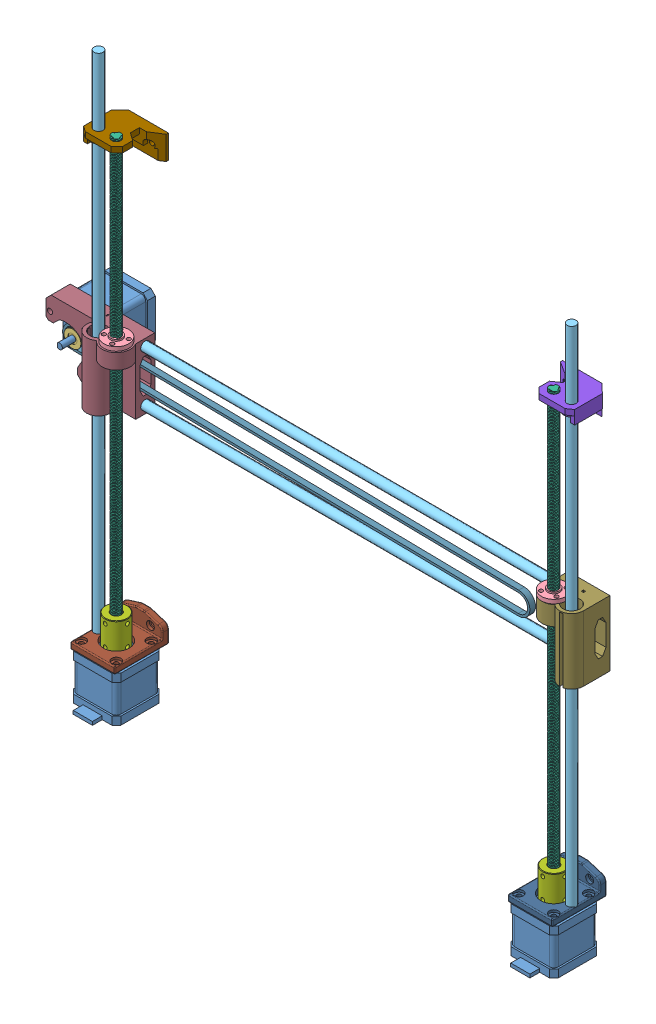
SolidWorks assembly XAssembly, configuration Default. Lengths in mm.
Overall size (485.02 523.02 93.11).
22 component instances, 14 part files, 37 mates.
Components (placement in the parent):
- 40-42 motor-1: 40-42 motor [Standard] at (83.3654 18.4973 -13.9547) x (-1 0 0) z (0 0 -1) size (42 64 50.7)
- 40-42 motor-2: 40-42 motor [Standard] at (-304.6346 18.4973 -13.9547) x (-1 0 0) z (0 0 -1) size (42 64 50.7)
- 624U pillow-1: 624U pillow [Standard] at (-70.3846 223.0937 -25.0811) x (1 0 0) z (0 -1 0) size (13 4 13)
- 2GT-pulley-1: 2GT-pulley [Standard] at (-298.4371 388.8614 -49.1082) x (0 0 1) z (0 1 0) size (16 15 15)
- flanged lead screw nut-1: flanged lead screw nut [Default] at (-380.1347 299.5237 42.4453) x (-0.892252 0 0.451538) z (0 -1 0) size (22 22 19.88)
- flanged lead screw nut-2: flanged lead screw nut [Default] at (7.8652 299.5237 42.4453) x (0.837169 0 0.546944) z (0 -1 0) size (22 22 19.88)
- 40-42 motor-3: 40-42 motor [Standard] at (-354.4079 323.9237 -22.4949) x (-1 0 0) z (0 1 0) size (42 64 50.7)
- BedSlider-1: BedSlider [Default] at (-396.8878 512.0237 35.3611) x (0.113678 0 -0.993518) z (0 -1 0) size (8 8 450)
- BedSlider-2: BedSlider [Default] at (19.3272 512.0237 36.7178) x (-0.378404 0 -0.925641) z (0 -1 0) size (8 8 450)
- Z threaded rod-1: Z threaded rod [Standard] at (-380.1346 84.0237 42.4453) x (0 0 -1) z (0 1 0) size (8.01 8.01 375.98)
- Z threaded rod-2: Z threaded rod [Standard] at (7.8394 454.0237 42.4545) x (-1 0 0) z (0 -1 0) size (8.01 8.01 375.98)
- Z coupler-1: Z coupler [Standard] at (-380.1346 75.0237 42.4453) size (20 26 20)
- Z coupler-2: Z coupler [Standard] at (7.8654 75.0237 42.4453) size (20 26 20)
- ztop holder Right-1: ztop holder Right [Default] at (-30.6346 447.0237 42.4453) x (-1 0 0) z (0 0 -1) size (43 21 35.75)
- ztop holder Left-1: ztop holder Left [Default] at (-380.1346 447.0237 42.4453) x (-1 0 0) z (0 0 -1) size (43 21 35.75)
- Y motor holder right-1: Y motor holder right [Default] at (7.8654 60.0237 42.4453) size (39.5 20 48)
- Y motor holder left-1: Y motor holder left [Default] at (-380.1346 60.0237 42.4453) size (39.5 20 48)
- Right z holder-1: Right z holder [Default] at (15.6154 267.0237 18.9453) x (0 1 0) z (1 0 0) size (58 34.5 38.04)
- Motor Mount-2: Motor Mount [Default] at (-369.4576 296.0237 35.9453) x (-1 0 0) z (0 0 -1) size (81.27 58 36)
- BedSlider-3: BedSlider [Default] at (33.1119 291.8257 20.521) x (0 0 -1) z (-1 0 0) size (8 8 450)
- BedSlider-4: BedSlider [Default] at (-420.7175 244.9609 20.2907) x (0 0.24335 -0.969938) z (1 0 0) size (8 8 450)
- belt-1: belt [Default] at (-397.4115 269.2854 25.1733) size (414.43 26.57 5)
Mates (geometry in assembly coordinates):
- Coincident1: coincident aligned: plane of 40-42 motor-1 through (28.8654 20.0237 72.1453) normal (0 -1 0); plane of 40-42 motor-2 through (-359.1346 20.0237 72.1453) normal (0 -1 0)
- Coincident3: coincident aligned: plane of 40-42 motor-1 through (-9.1416 60.0237 21.4453) normal (0 0 -1); plane of 40-42 motor-2 through (-397.1416 60.0237 21.4453) normal (0 0 -1)
- Concentric3: concentric aligned: cylinder of 2GT-pulley-1 through (-429.9079 267.5237 16.0835) axis (0 0 -1) radius 2.5; cylinder of 40-42 motor-3 through (-429.9079 267.5237 43.0315) axis (0 0 -1) radius 2.5
- Coincident12: coincident anti-aligned: plane of 40-42 motor-2 through (-380.1346 62.0237 42.4453) normal (0 1 0); plane of Z coupler-1 through (-380.1346 62.0237 42.4453) normal (0 -1 0)
- Concentric4: concentric aligned: cylinder of 40-42 motor-2 through (-380.1346 84.0237 42.4453) axis (0 -1 0) radius 2.5; circle of Z coupler-1
- Coincident13: coincident anti-aligned: plane of 40-42 motor-1 through (7.8654 62.0237 42.4453) normal (0 1 0); plane of Z coupler-2 through (7.8654 62.0237 42.4453) normal (0 -1 0)
- Concentric5: concentric anti-aligned: cylinder of 40-42 motor-1 through (7.8654 84.0237 42.4453) axis (0 -1 0) radius 2.5; cylinder of Z coupler-2 through (7.8654 88.0237 42.4453) axis (0 1 0) radius 4
- Coincident14: coincident anti-aligned: plane of 40-42 motor-2 through (-380.1346 84.0237 42.4453) normal (0 1 0); plane of Z threaded rod-1 through (-380.1346 84.0237 42.4453) normal (0 -1 0)
- Coincident15: coincident anti-aligned: plane of 40-42 motor-1 through (7.8654 84.0237 42.4453) normal (0 1 0); plane of Z threaded rod-2 through (7.8394 84.0237 42.4545) normal (0 -1 0)
- Distance3: distance = 346 mm anti-aligned: plane of 40-42 motor-2 through (-359.1346 60.0237 59.4523) normal (1 0 0); plane of 40-42 motor-1 through (-13.1346 60.0237 59.4523) normal (-1 0 0)
- Coincident19: coincident anti-aligned: plane of 40-42 motor-1 through (7.8654 60.0237 42.4453) normal (0 1 0); plane of Y motor holder right-1 through (7.8654 60.0237 42.4453) normal (0 -1 0)
- Concentric7: concentric anti-aligned: circle of 40-42 motor-1; circle of Y motor holder right-1
- Concentric8: concentric anti-aligned: circle of BedSlider-2; circle of Y motor holder right-1
- Concentric10: concentric anti-aligned: circle of BedSlider-2; circle of Right z holder-1
- Distance4: distance = 150 mm anti-aligned: plane of Right z holder-1 through (34.1154 238.0237 35.9453) normal (0 -1 0); plane of Z coupler-2 through (7.8654 88.0237 42.4453) normal (0 1 0)
- Coincident25: coincident anti-aligned: plane of 40-42 motor-2 through (-380.1346 60.0237 42.4453) normal (0 1 0); plane of Y motor holder left-1 through (-380.1346 60.0237 42.4453) normal (0 -1 0)
- Concentric11: concentric anti-aligned: circle of 40-42 motor-2; circle of Y motor holder left-1
- Concentric14: concentric anti-aligned: circle of BedSlider-1; circle of Y motor holder left-1
- Coincident26: coincident anti-aligned: plane of BedSlider-1 through (-395.8846 62.0237 42.4453) normal (0 -1 0); plane of Y motor holder left-1 through (-395.8846 62.0237 42.4453) normal (0 1 0)
- Coincident27: coincident anti-aligned: plane of BedSlider-2 through (23.6154 62.0237 42.4453) normal (0 -1 0); plane of Y motor holder right-1 through (23.6154 62.0237 42.4453) normal (0 1 0)
- Concentric15: concentric anti-aligned: circle of 40-42 motor-1; circle of Y motor holder right-1
- Concentric16: concentric anti-aligned: circle of 40-42 motor-2; circle of Y motor holder left-1
- Concentric19: concentric anti-aligned: circle of BedSlider-1; circle of Motor Mount-2
- Coincident33: coincident aligned: plane of Right z holder-1 through (34.1154 296.0237 35.9453) normal (0 1 0); plane of Motor Mount-2 through (-369.4576 296.0237 18.9453) normal (0 1 0)
- Concentric20: concentric anti-aligned: circle of 40-42 motor-3; circle of Motor Mount-2
- Concentric21: concentric anti-aligned: circle of 40-42 motor-3; circle of Motor Mount-2
- Distance5: distance = 60 mm aligned: plane of BedSlider-2 through (23.6154 512.0237 42.4453) normal (0 1 0); plane of ztop holder Right-1 through (-30.6346 452.0237 42.4453) normal (0 1 0)
- Distance6: distance = 60 mm aligned: plane of BedSlider-1 through (-395.8846 512.0237 42.4453) normal (0 1 0); plane of ztop holder Left-1 through (-380.1346 452.0237 42.4453) normal (0 1 0)
- Concentric24: concentric anti-aligned: cylinder of BedSlider-1 through (-395.8846 62.0237 42.4453) axis (0 1 0) radius 4; cylinder of ztop holder Left-1 through (-395.8846 452.0237 42.4453) axis (0 -1 0) radius 4
- Concentric26: concentric aligned: cylinder of Motor Mount-2 through (-404.4576 290.0237 27.4453) axis (1 0 0) radius 4.05; cylinder of BedSlider-3 through (-416.8881 290.0237 27.4453) axis (1 0 0) radius 4
- Concentric27: concentric anti-aligned: cylinder of Motor Mount-2 through (-404.4576 245.0237 27.4453) axis (1 0 0) radius 4.05; cylinder of BedSlider-4 through (29.2825 245.0237 27.4453) axis (-1 0 0) radius 4
- Concentric28: concentric anti-aligned: circle of 624U pillow-1; circle of Right z holder-1
- Distance7: distance = 3 mm anti-aligned: plane of Right z holder-1 through (34.1154 258.0237 22.4453) normal (0 0 1); plane of 624U pillow-1 through (13.1154 260.4121 25.4453) normal (0 0 -1)
- Coincident38: coincident anti-aligned: plane of flanged lead screw nut-1 through (-389.9495 296.0237 47.4122) normal (0 -1 0); plane of Motor Mount-2 through (-369.4576 296.0237 18.9453) normal (0 1 0)
- Concentric29: concentric anti-aligned: circle of flanged lead screw nut-1; circle of Motor Mount-2
- Coincident39: coincident anti-aligned: plane of flanged lead screw nut-2 through (17.0741 296.0237 48.4617) normal (0 -1 0); plane of Right z holder-1 through (34.1154 296.0237 35.9453) normal (0 1 0)
- Concentric30: concentric anti-aligned: circle of flanged lead screw nut-2; circle of Right z holder-1
